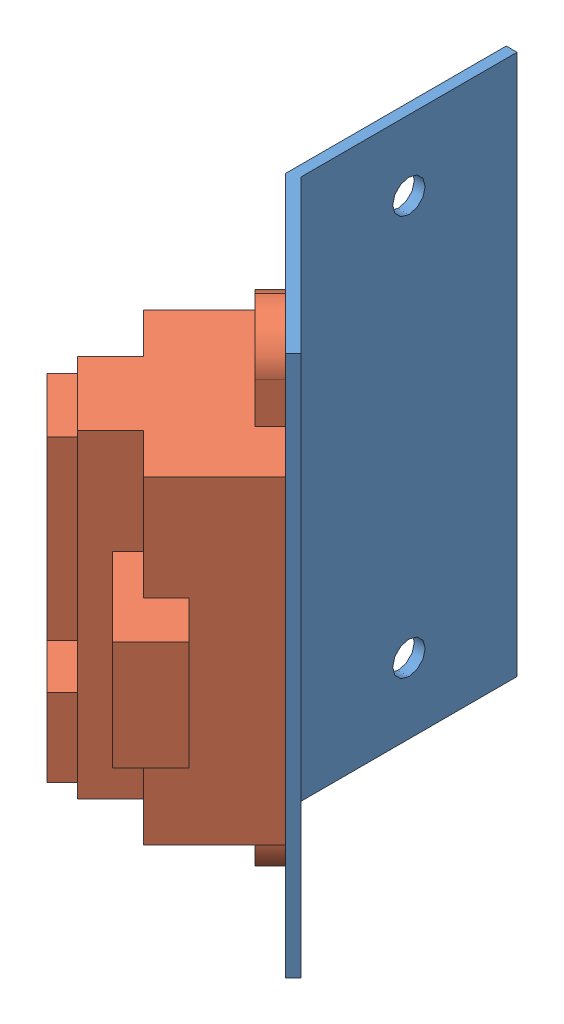
SolidWorks assembly capteur_cote, configuration Default. Lengths in mm.
Overall size (27.93 50 49.03).
2 component instances, 2 part files, 3 mates.
Components (placement in the parent):
- corniere_angle45_H50_l20-1: corniere_angle45_H50_l20 [Default] at (-21.0346 -24.5362 2.9851) size (15.14 50 34.85)
- GP2D12-1: GP2D12 [Default] at (-6.9885 -14.2862 17.0313) x (0 1 0) z (0.707107 0 0.707107) size (44.5 15.6 23.9)
Mates (geometry in assembly coordinates):
- Coïncidente1: coincident anti-aligned: plane of corniere_angle45_H50_l20-1 through (-6.5995 25.4638 17.4202) normal (-0.707107 0 0.707107); plane of GP2D12-1 through (-20.3528 -14.2862 3.6669) normal (0.707107 0 -0.707107)
- Coaxiale3: concentric aligned: cylinder of corniere_angle45_H50_l20-1; cylinder of GP2D12-1
- Coaxiale4: concentric aligned: cylinder of corniere_angle45_H50_l20-1; cylinder of GP2D12-1
